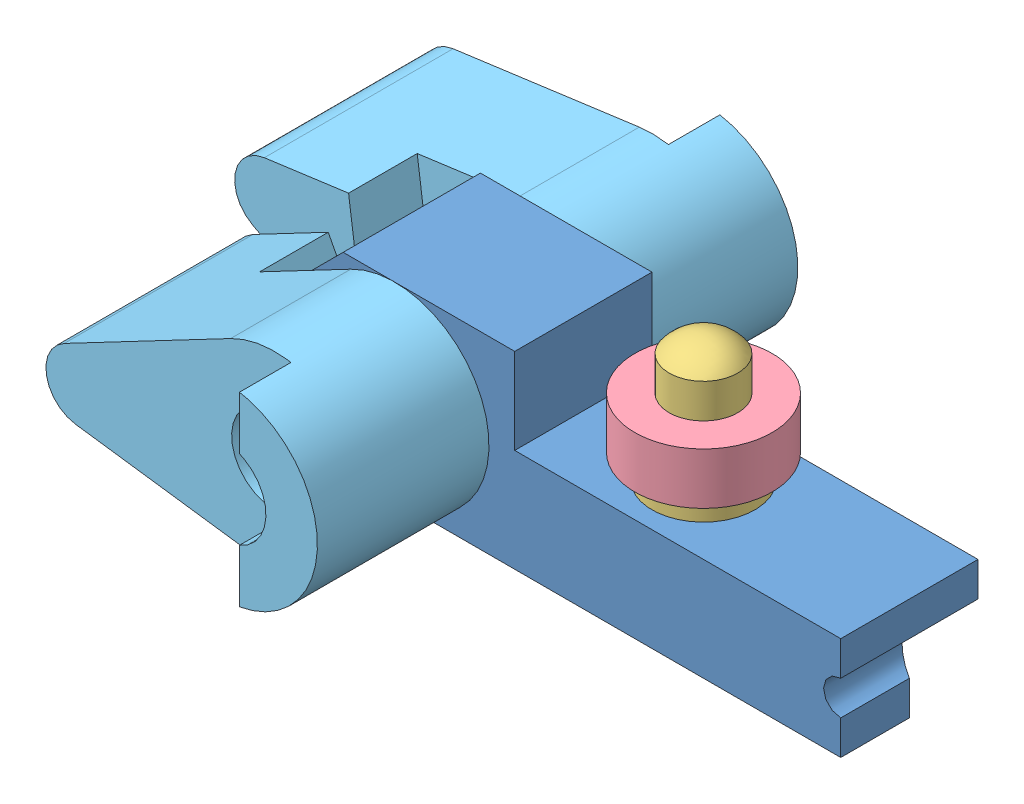
SolidWorks assembly penne, configuration Défaut. Lengths in mm.
Overall size (40.25 15.66 28).
6 component instances, 5 part files, 14 mates.
Components (placement in the parent):
- Pièce5-1: Pièce5 [Défaut] at (-12.8916 -3.2369 -4) size (32 11 8)
- Pièce4-1: Pièce4 [Défaut] at (-6.8916 2.2631 10.5) x (0 0 -1) z (1 0 0) size (21 6 6)
- Pièce7-1: Pièce7 [Défaut] at (7.1084 -5.2369 0) x (0 1 0) z (0 0 1) size (15.4 6 6)
- Pièce6-1: Pièce6 [Défaut] at (7.1084 4.1631 0) x (0.982348 0 0.187064) z (0 1 0) size (8 8 3)
- Pièce3-3: Pièce3 [Défaut] at (-6.8916 2.2631 -14) x (0.984808 -0.173648 0) z (0 0 1) size (19 11 14)
- Pièce3-4: Pièce3 [Défaut] at (-6.8916 2.2631 14) x (0.984808 0.173648 0) z (0 0 -1) size (19 11 14)
Mates (geometry in assembly coordinates):
- Coaxiale1: concentric anti-aligned: cylinder of Pièce5-1 through (-6.8916 2.2631 4) axis (0 0 -1) radius 3; cylinder of Pièce4-1 through (-6.8916 2.2631 65.3246) axis (0 0 1) radius 3
- Coïncidente1: coincident aligned: plane of Pièce5-1 through (-12.8916 2.7631 4) normal (0 0 1); plane of Pièce4-1 through (-6.8916 4.7631 4) normal (0 0 1)
- Coaxiale5: concentric anti-aligned: cylinder of Pièce5-1 through (7.1084 7.7631 0) axis (0 -1 0) radius 2; cylinder of Pièce7-1 through (7.1084 9.1631 0) axis (0 1 0) radius 2
- Coïncidente4: coincident anti-aligned: plane of Pièce5-1 through (19.1084 2.7631 4) normal (0 1 0); plane of Pièce7-1 through (5.1084 2.7631 0) normal (0 -1 0)
- Coaxiale6: concentric anti-aligned: cylinder of Pièce7-1 through (7.1084 9.1631 0) axis (0 1 0) radius 2; cylinder of Pièce6-1 through (7.1084 7.1631 0) axis (0 -1 0) radius 2
- Coïncidente5: coincident anti-aligned: plane of Pièce7-1 through (4.1084 4.1631 0) normal (0 1 0); plane of Pièce6-1 through (7.1084 4.1631 0) normal (0 -1 0)
- Coaxiale2: concentric anti-aligned: cylinder of Pièce4-1 through (-6.8916 2.2631 65.3246) axis (0 0 1) radius 2.5; cylinder of Pièce3-3 through (-6.8916 2.2631 0) axis (0 0 -1) radius 2.5
- Coïncidente2: coincident anti-aligned: plane of Pièce5-1 through (-12.8916 2.7631 -4) normal (0 0 -1); plane of Pièce3-3 through (-6.8916 2.2631 -4) normal (0 0 1)
- Parallèle1: parallel aligned: plane of Pièce5-1 through (-12.8916 -3.2369 4) normal (-1 0 0); plane of Pièce3-3 through (-5.9366 5.9476 -11) normal (-1 0 0)
- Coaxiale4: concentric aligned: cylinder of Pièce4-1 through (-6.8916 2.2631 65.3246) axis (0 0 1) radius 2.5; cylinder of Pièce3-4 through (-6.8916 2.2631 0) axis (0 0 1) radius 2.5
- Coïncidente3: coincident anti-aligned: plane of Pièce5-1 through (-12.8916 2.7631 4) normal (0 0 1); plane of Pièce3-4 through (-6.8916 2.2631 4) normal (0 0 -1)
- Coïncidente6: coincident aligned: plane of Pièce3-3 through (-5.9366 5.9476 -11) normal (-1 0 0); plane of Pièce3-4 through (-5.9366 -1.4213 11) normal (-1 0 0)
- Coïncidente9: coincident aligned: plane of Pièce3-3 through (-7.6303 7.7133 0) normal (-0.134314 0.990939 0); plane of Pièce3-4
- Parallèle2: parallel aligned: plane of Pièce5-1 through (-12.8916 -3.2369 4) normal (-1 0 0); plane of Pièce3-4
